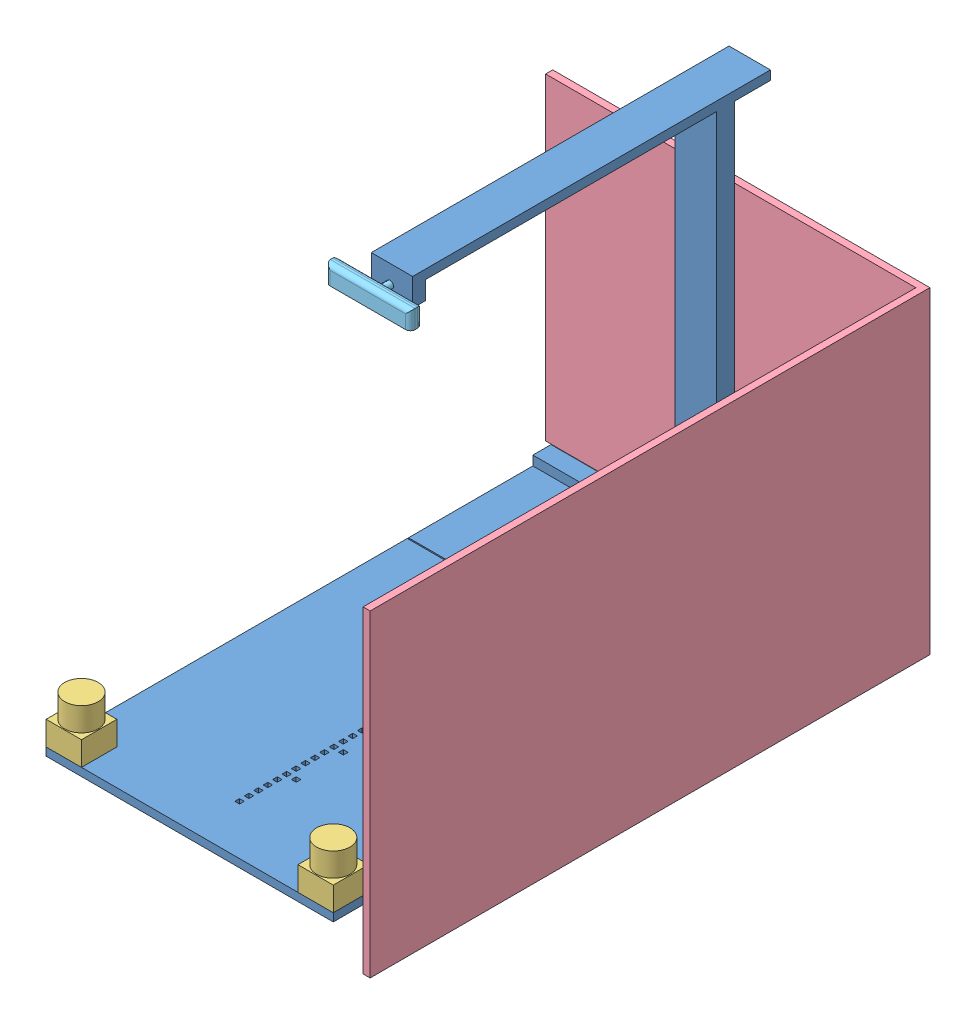
SolidWorks assembly tabletop_link, configuration Default. Lengths in mm.
Overall size (800.31 871.04 1248.7).
5 component instances, 5 part files, 13 mates.
Components (placement in the parent):
- Plywood-1: Plywood [Default] at origin size (609 871.04 1184.9)
- PowerSupply-1: PowerSupply [Default] at (241.3 17 -266.3) x (-1 0 0) z (0 1 0) size (145 157 87)
- EStopButtons-1: EStopButtons [Default] at (0 17 0) x (-1 0 0) z (0 1 0) size (609 75 100.8)
- Wall-1: Wall [Default] at (85.6891 0 24.7806) size (800.31 674.14 1187.5)
- Asus Xtion Pro-1: Asus Xtion Pro [Default] at (-1.475 805.2 284.195) x (0 0 1) z (0 1 0) size (47 180 39)
Mates (geometry in assembly coordinates):
- InPlace2: in place: plane of ? through (-233.7125 129.9307 599.4491) normal (0 1 0); plane of ? through (0 129.9307 0) normal (0 1 0); moOrthogonalPlaneRef_w of ? through (-233.7125 129.9307 599.4491) normal (0 1 0); unknown of ?; plane of ? through (-233.7125 129.9307 599.4491) normal (0 1 0); line of ? through (-55 0 129.9307) axis (0 -1 0); plane of Plywood-1 through (-305 17 710.27) normal (0 1 0); unknown of EStopButtons-1
- Coincident1: coincident aligned: plane of Plywood-1; plane of EStopButtons-1
- Coincident2: coincident aligned: moOrthogonalPlaneRef_w of Plywood-1 through (0 17 0) normal (0 0 1); plane of EStopButtons-1
- Coincident3: coincident anti-aligned: moOrthogonalPlaneRef_w of Plywood-1 through (0 17 0) normal (1 0 0); plane of EStopButtons-1
- Coincident3: coordinate: point of Plywood-1; point of assembly
- Coincident4: coincident anti-aligned: plane of Plywood-1 through (-41.475 843.8 284.195) normal (0 0 1); plane of Asus Xtion Pro-1 through (-1.475 805.2 284.195) normal (0 0 -1)
- Coincident5: coincident aligned: plane of Plywood-1 through (0 785.7 0) normal (0 -1 0); plane of Asus Xtion Pro-1 through (88.525 785.7 331.195) normal (0 -1 0)
- Distance2: distance = 50 mm aligned: plane of Asus Xtion Pro-1 through (-91.475 824.7 331.195) normal (-1 0 0); plane of Plywood-1 through (-41.475 824.4 -360.53) normal (-1 0 0)
- Coincident14: coincident anti-aligned: plane of Plywood-1 through (304 37 -322.03) normal (0 0 1); plane of PowerSupply-1 through (-63.7 104 -322.03) normal (0 0 -1)
- Coincident15: coincident anti-aligned: plane of Plywood-1 through (-305 17 710.27) normal (0 1 0); plane of PowerSupply-1 through (-63.7 17 -165.03) normal (0 -1 0)
- Distance3: distance = 241.3 mm aligned: plane of PowerSupply-1 through (-63.7 104 -322.03) normal (-1 0 0); plane of Plywood-1 through (-305 696.8839 -360.53) normal (-1 0 0)
- Coincident17: coincident anti-aligned: plane of Plywood-1 through (-41.475 824.4 -398.43) normal (0 0 -1); plane of Wall-1 through (431 674.1356 -398.43) normal (0 0 1)
- Distance4: distance = 127 mm anti-aligned: plane of EStopButtons-1 through (304 67.8 710.27) normal (1 0 0); plane of Wall-1 through (431 674.1356 774.067) normal (-1 0 0)
